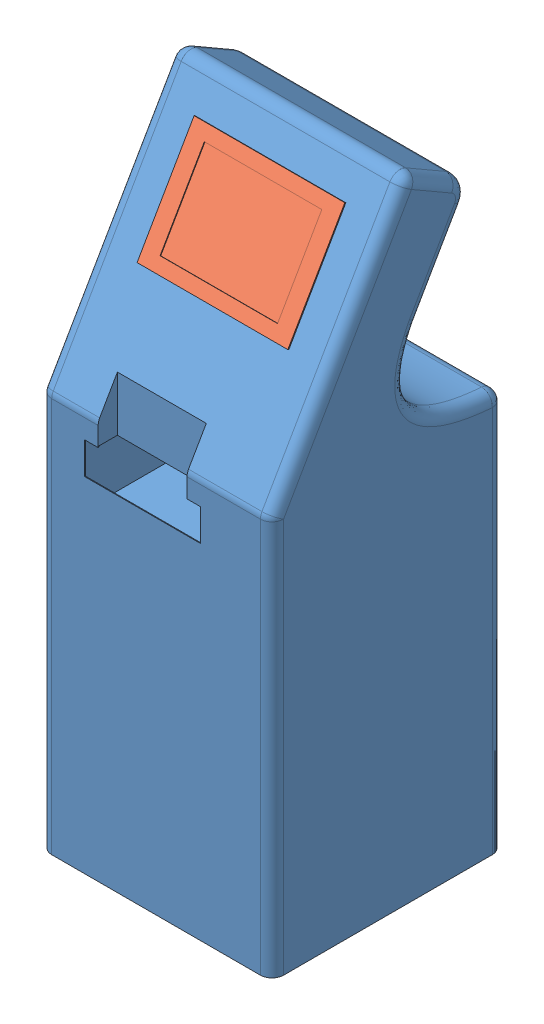
SolidWorks assembly 清洗机装配图, configuration 默认. Lengths in mm.
Overall size (603.38 1625.24 600).
2 component instances, 2 part files, 4 mates.
Components (placement in the parent):
- 清洗机主体 导图版-1: 清洗机主体 导图版 [默认] at (-136.7388 -922.2803 0) size (603.38 1625.24 600)
- 触摸屏-1: 触摸屏 [默认] at (-137.7388 495.9 79.3481) x (-1 0 0) z (0 -0.866025 0.5) size (390 63 295)
Mates (geometry in assembly coordinates):
- 平行1: parallel anti-aligned: line of 清洗机主体 导图版-1 through (49.7612 374.0225 146.25) axis (0 0.866025 -0.5); line of 触摸屏-1 through (57.2612 622.1388 3) axis (0 -0.866025 0.5)
- 距离2: distance = 0 mm anti-aligned: plane of 触摸屏-1 through (-332.7388 622.1388 3) normal (0 -0.5 -0.866025); plane of 清洗机主体 导图版-1 through (-436.7388 107.7197 300) normal (0 0.5 0.866025)
- 距离3: distance = 1 mm anti-aligned: plane of 清洗机主体 导图版-1 through (49.7612 601.5096 -19.7308) normal (-1 0 0); plane of 触摸屏-1 through (48.7612 600.6436 -19.2308) normal (1 0 0)
- 距离4: distance = 1 mm anti-aligned: plane of 触摸屏-1 through (48.7612 358.1565 120.7692) normal (0 -0.866025 0.5); plane of 清洗机主体 导图版-1 through (-323.2388 359.0225 120.2692) normal (0 0.866025 -0.5)
